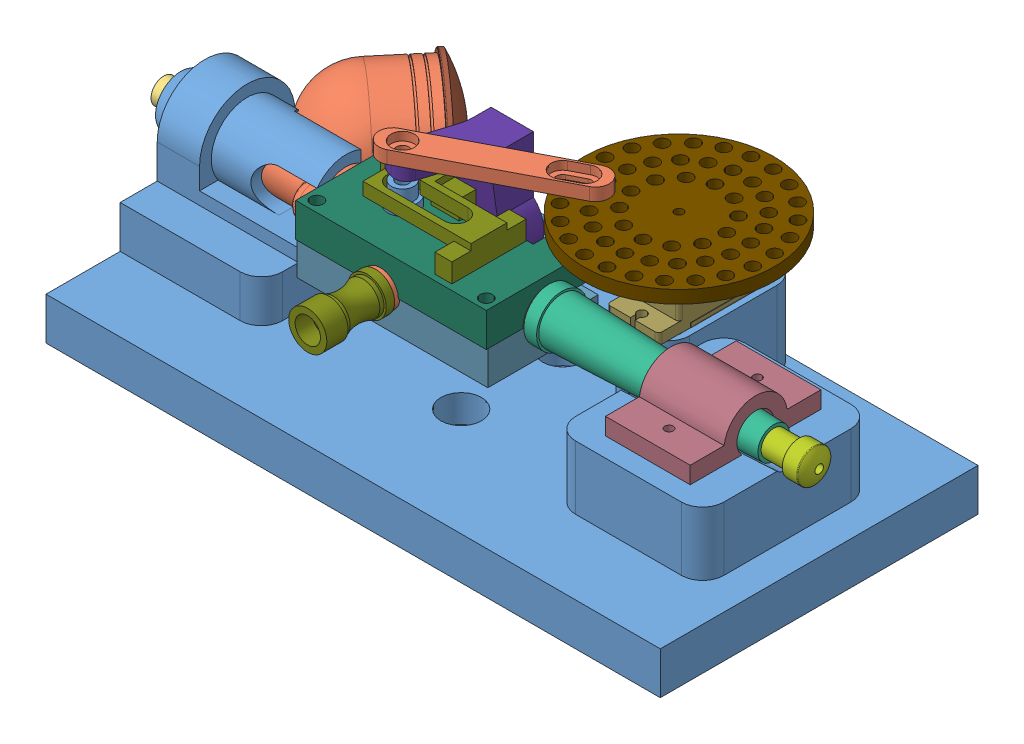
SolidWorks assembly MontagemAerografo, configuration Valor predeterminado. Lengths in mm.
Overall size (154.73 50 79.98).
39 component instances, 38 part files, 24 mates.
Components (placement in the parent):
- MontagemSuporteAerografo-1: MontagemSuporteAerografo [Valor predeterminado] at (-13.8109 -20.2031 5.6544) size (150.65 39.25 75)
- Aerografo-2: Aerografo [Valor predeterminado] at (-36.0272 -78.0511 148.5886) x (1 0 0) z (0 1 0) size (154.73 72.05 35.62)
  - Corpo 1-1: Corpo 1 [Valor predeterminado] at (-54.0783 -2.0658 80) size (80 49.19 25)
  - Encaixe_Agulha-1: Encaixe_Agulha [Valor predeterminado] at (14.9217 -2.0658 80) x (-1 0 0) z (0 0 1) size (4 9 9)
  - Parafuso-1: Parafuso [Valor predeterminado] at (13.8087 -3.2658 80.4618) x (-0.887002 0 -0.461767) z (-0.461767 0 0.887002) size (4 5.16 4)
  - Fixação_Agulha_3-1: Fixação_Agulha_3 [Valor predeterminado] at (5.3054 -2.0658 80) x (1 0 0) z (0 -1 0) size (42.04 5 5)
  - Mola_Agulha-1: Mola_Agulha [Valor predeterminado] at (17.3054 -2.0658 80) x (0 -0.999777 -0.021106) z (0 -0.021106 0.999777) size (5.15 14.82 5.77)
  - Fixação_Agulha_2-1: Fixação_Agulha_2 [Valor predeterminado] at (14.9217 -2.0658 80) x (1 0 0) z (0 -0.937211 0.348763) size (18 9 9)
  - Alavanca-1: Alavanca [Valor predeterminado] at (-1.0783 6.1935 80) x (0 -1 0) z (0 0 1) size (17 11 11)
  - Alavanca_Mecanismo-1: Alavanca_Mecanismo [Valor predeterminado] at (0.9217 -13.3065 80) x (0 0 -1) z (1 0 0) size (2 8.5 3)
  - Rebite-1: Rebite [Valor predeterminado] at (0.9217 -5.8065 80) size (1 1 3)
  - Eixo_Valvula-1: Eixo_Valvula [Valor predeterminado] at (0.9217 -31.3065 80) x (-0.831662 0 -0.555282) z (0.555282 0 -0.831662) size (4.5 18.5 4.5)
  - Mola_Valvula-1: Mola_Valvula [Valor predeterminado] at (0.9217 -16.8065 80) x (-0.392534 0 -0.919737) z (-0.919737 0 0.392534) size (3.81 13.46 4.27)
  - O-ring_Válvula 1-1: O-ring_Válvula 1 [Valor predeterminado] at (0.9217 -16.3065 80) x (-0.831662 0 -0.555282) z (0 1 0) size (4.5 4.5 1)
  - O-ring_Válvula 2-1: O-ring_Válvula 2 [Valor predeterminado] at (0.9217 -18.0658 80) x (0.996046 0 0.088843) z (0 1 0) size (7 7 1)
  - Tampa_Válvula-1: Tampa_Válvula [Valor predeterminado] at (0.9217 -30.0658 80) x (-0.831662 0 -0.555282) z (0 1 0) size (4.39 4.5 0.5)
  - Valvula-1: Valvula [Valor predeterminado] at (0.9217 -14.0658 80) x (0.996046 0 0.088843) z (-0.088843 0 0.996046) size (9 20 9)
  - Placa_Mola-2: Placa_Mola [Valor predeterminado] at (3.6284 -5.6712 76.75) x (0 0 1) z (-0.97249 -0.232944 0) size (6.17 10.12 2.5)
  - O-ring_Bico-1: O-ring_Bico [Valor predeterminado] at (-51.3283 -2.0658 80) x (0 0 -1) z (1 0 0) size (7.5 7.5 0.25)
  - O-ring_Corpo-1: O-ring_Corpo [Valor predeterminado] at (0.9217 -12.0658 80) x (0.999142 0 0.041416) z (0 -1 0) size (4 4 0.5)
  - Bico 1-1: Bico 1 [Valor predeterminado] at (-61.0783 -2.0658 80) size (10 9.5 9.5)
  - Bico 2-1: Bico 2 [Valor predeterminado] at (-65.0783 -2.0658 80) x (1 0 0) z (0 0.382891 0.923793) size (6.5 7 7)
  - Biqueira-1: Biqueira [Valor predeterminado] at (-61.0783 -2.0658 80) x (1 0 0) z (0 0.183184 0.983079) size (6.2 3 3)
  - Biqueira 2-1: Biqueira 2 [Valor predeterminado] at (-56.0783 -2.0658 80) x (1 0 0) z (0 0.973222 0.229866) size (10 5 5)
  - Corpo 2-1: Corpo 2 [Valor predeterminado] at (21.9217 -2.0658 80) x (1 0 0) z (0 0.71215 0.702027) size (57 12 12)
  - Encaixe_Fundo-1: Encaixe_Fundo [Valor predeterminado] at (57.7217 -2.0658 80) size (31.93 8 8)
  - Fixação_Agulha-1: Fixação_Agulha [Valor predeterminado] at (51.1502 -2.0658 80) x (-1 0 0) z (0 -0.904496 -0.426482) size (10 6 6)
  - O-Ring_Encaixe_Fundo-1: O-Ring_Encaixe_Fundo [Valor predeterminado] at (77.7217 -2.0658 80) x (0 0 -1) z (1 0 0) size (6 6 1.2)
  - Agulha-1: Agulha [Valor predeterminado] at (-61.3498 -2.0658 80) x (1 0 0) z (0 0.994994 0.099935) size (128.5 1 1)
  - Tampa-1: Tampa [Valor predeterminado] at (-27.1715 20.4042 80) x (-0.310383 0.260442 0.914239) z (-0.700348 0.587661 -0.405176) size (27 8 27)
- SG90 - Micro Servo 9g - Tower Pro.1-1: SG90 - Micro Servo 9g - Tower Pro.1 [Peça] at (3.4511 -3.1511 128.4544) x (0 0 -1) z (1 0 0) size (32.1 29.95 12.4)
- SuporteCorpoAerografoVer3Part2-1: SuporteCorpoAerografoVer3Part2 [Valor predeterminado] at (-13.8989 1.9489 150.6574) x (0 0 -1) z (0 -1 0) size (30.87 20 10.5)
- GatilhoSuporteInferior-1: GatilhoSuporteInferior [Valor predeterminado] at (-90.1055 1.9489 150.5166) x (1 0 0) z (0 1 0) size (45 26.06 8.23)
- GatilhoSuporteSuperiorVer3-1: GatilhoSuporteSuperiorVer3 [Valor predeterminado] at (-90.1055 1.9489 150.8748) x (1 0 0) z (0 1 0) size (45 26.06 8.34)
- GatilhoSuporteCaminhoVer2-1: GatilhoSuporteCaminhoVer2 [Valor predeterminado] at (-40.8359 9.9466 146.4543) size (30.5 6 17.7)
- GatilhoBotao&HasteBotao_SuporteVer4-1: GatilhoBotao&HasteBotao_SuporteVer4 [Valor predeterminado] at (-35.1055 1.9489 142.8951) x (-1 0 0) z (0 -1 0) size (16.72 23.02 26.5)
- GatilhoServo-1: GatilhoServo [Valor predeterminado] at (3.4511 14.3489 133.6044) x (0.990141 0 -0.140076) z (0.140076 0 0.990141) size (45 6.6 45)
- GatilhoSuporteCorredicaVer2-1: GatilhoSuporteCorredicaVer2 [Valor predeterminado] at (-40.6688 10.9466 154.6961) size (7 5 7)
- GatilhoHasteServo_SuporteVer4-1: GatilhoHasteServo_SuporteVer4 [Valor predeterminado] at (-26.4762 20.9489 147.3089) x (-0.887035 0 0.461701) z (-0.461701 0 -0.887035) size (42 3 6.5)
Mates (geometry in assembly coordinates):
- Concêntrico3: concentric aligned: cylinder of MontagemSuporteAerografo-1 through (-58.0533 1.9489 150.6544) axis (-1 0 0) radius 6; cone of Aerografo-2/Corpo 1-1 through (-77.1055 1.9489 150.6544) axis (-1 0 0)
- Paralelo4: parallel anti-aligned: plane of MontagemSuporteAerografo-1 through (53.6011 -16.0511 113.1544) normal (0 1 0); plane of Aerografo-2/Alavanca-1 through (-35.1055 0.4489 153.3951) normal (0 -1 0)
- Tangente2: tangent aligned: cylinder of MontagemSuporteAerografo-1 through (-67.3989 1.9489 122.1544) axis (0 0 1) radius 10; face of Aerografo-2/Corpo 1-1
- Coincidente7: coincident anti-aligned: plane of MontagemSuporteAerografo-1 through (3.4511 1.9989 128.4544) normal (0 1 0); plane of SG90 - Micro Servo 9g - Tower Pro.1-1 through (8.7011 1.9989 143.6544) normal (0 -1 0)
- Concêntrico4: concentric aligned: cylinder of MontagemSuporteAerografo-1 through (3.4511 -4.0011 114.5544) axis (0 1 0) radius 1; cylinder of SG90 - Micro Servo 9g - Tower Pro.1-1 through (3.4511 -13.7011 114.5544) axis (0 1 0) radius 1.1
- Coincidente8: coincident anti-aligned: plane of MontagemSuporteAerografo-1 through (46.1011 -1.0511 130.6544) normal (0 1 0); plane of SuporteCorpoAerografoVer3Part2-1 through (46.1011 -1.0511 135.2244) normal (0 -1 0)
- Concêntrico5: concentric aligned: cylinder of MontagemSuporteAerografo-1 through (28.6011 -7.0511 140.2244) axis (0 1 0) radius 1; cylinder of SuporteCorpoAerografoVer3Part2-1 through (28.6011 -1.0511 140.2244) axis (0 1 0) radius 1
- Paralelo5: parallel aligned: cylinder of MontagemSuporteAerografo-1 through (28.6011 -7.0511 161.0844) axis (0 1 0) radius 1; cylinder of SuporteCorpoAerografoVer3Part2-1 through (28.6011 -1.0511 161.0905) axis (0 1 0) radius 1
- Concêntrico7: concentric aligned: cylinder of Aerografo-2/Corpo 1-1 through (-35.1055 1.9489 153.9581) axis (0 0 -1) radius 4.25; cylinder of GatilhoSuporteInferior-1 through (-35.1055 1.9489 153.8203) axis (0 0 -1) radius 4.25
- Distância1: distance = 1.5 mm anti-aligned: plane of Aerografo-2/Valvula-1 through (-37.7949 1.709 166.6544) normal (0 0 -1); plane of GatilhoSuporteInferior-1 through (-10.1055 -6.0362 165.1544) normal (0 0 1)
- Paralelo6: parallel anti-aligned: plane of MontagemSuporteAerografo-1 through (53.6011 -16.0511 113.1544) normal (0 1 0); plane of GatilhoSuporteInferior-1 through (-10.1055 -6.0362 139.0962) normal (0 -1 0)
- Concêntrico10: concentric aligned: cylinder of Aerografo-2/Corpo 1-1 through (-35.1055 1.9489 153.9581) axis (0 0 -1) radius 4.25; cylinder of GatilhoSuporteSuperiorVer3-1 through (-35.1055 1.9489 154.1784) axis (0 0 -1) radius 4.25
- Concêntrico11: concentric aligned: cylinder of GatilhoSuporteInferior-1 through (-51.1055 43.9638 142.1645) axis (0 -1 0) radius 1.6; cylinder of GatilhoSuporteSuperiorVer3-1 through (-51.1055 11.9489 142.1645) axis (0 -1 0) radius 1.6
- Coincidente11: coincident anti-aligned: plane of GatilhoSuporteSuperiorVer3-1 through (-10.1055 9.9466 165.5125) normal (0 1 0); plane of GatilhoSuporteCaminhoVer2-1 through (-31.5859 9.9466 150.4543) normal (0 -1 0)
- Coincidente12: coincident aligned: plane of GatilhoSuporteSuperiorVer3-1 through (-18.1055 46.9489 146.4543) normal (0 0 -1); plane of GatilhoSuporteCaminhoVer2-1 through (-40.8359 9.9466 146.4543) normal (0 0 -1)
- Concêntrico12: concentric aligned: cylinder of Aerografo-2/Alavanca-1 through (-35.1055 1.9489 138.3951) axis (0 0 1) radius 5.5; cylinder of GatilhoBotao&HasteBotao_SuporteVer4-1 through (-35.1055 1.9489 138.3951) axis (0 0 1) radius 5.75
- Coincidente13: coincident anti-aligned: plane of Aerografo-2/Alavanca-1 through (-35.1055 1.9489 138.3951) normal (0 0 -1); plane of GatilhoBotao&HasteBotao_SuporteVer4-1 through (-35.1055 1.9489 138.3951) normal (0 0 1)
- Concêntrico13: concentric anti-aligned: cone of SG90 - Micro Servo 9g - Tower Pro.1-1 through (3.4511 16.1489 133.6044) axis (0 1 0); cylinder of GatilhoServo-1 through (3.4511 17.9489 133.6044) axis (0 -1 0) radius 3.5
- Paralelo7: parallel anti-aligned: plane of MontagemSuporteAerografo-1 through (-2.6989 -15.0511 117.1544) normal (1 0 0); plane of SG90 - Micro Servo 9g - Tower Pro.1-1 through (-2.6489 4.4989 143.6544) normal (-1 0 0)
- Coincidente16: coincident anti-aligned: plane of GatilhoSuporteCaminhoVer2-1 through (-45.0859 12.9466 159.6543) normal (0 -1 0); plane of GatilhoSuporteCorredicaVer2-1 through (-40.6688 12.9466 154.6961) normal (0 1 0)
- Concêntrico14: concentric aligned: cylinder of GatilhoBotao&HasteBotao_SuporteVer4-1 through (-40.6688 -5.5511 154.6961) axis (0 1 0) radius 1.5; cylinder of GatilhoSuporteCorredicaVer2-1 through (-40.6688 11.9466 154.6961) axis (0 1 0) radius 1.5
- Coincidente17: coincident anti-aligned: plane of GatilhoServo-1 through (3.4511 20.9489 133.6044) normal (0 1 0); plane of GatilhoHasteServo_SuporteVer4-1 through (-26.4762 20.9489 147.3089) normal (0 -1 0)
- Concêntrico15: concentric aligned: cylinder of GatilhoBotao&HasteBotao_SuporteVer4-1 through (-40.6688 -5.5511 154.6961) axis (0 1 0) radius 1.5; cylinder of GatilhoHasteServo_SuporteVer4-1 through (-40.6688 20.9489 154.6961) axis (0 1 0) radius 1.5
- Coincidente18: coincident anti-aligned: plane of GatilhoBotao&HasteBotao_SuporteVer4-1 through (-40.1055 20.9489 142.8951) normal (0 1 0); plane of GatilhoHasteServo_SuporteVer4-1 through (-26.4762 20.9489 147.3089) normal (0 -1 0)
